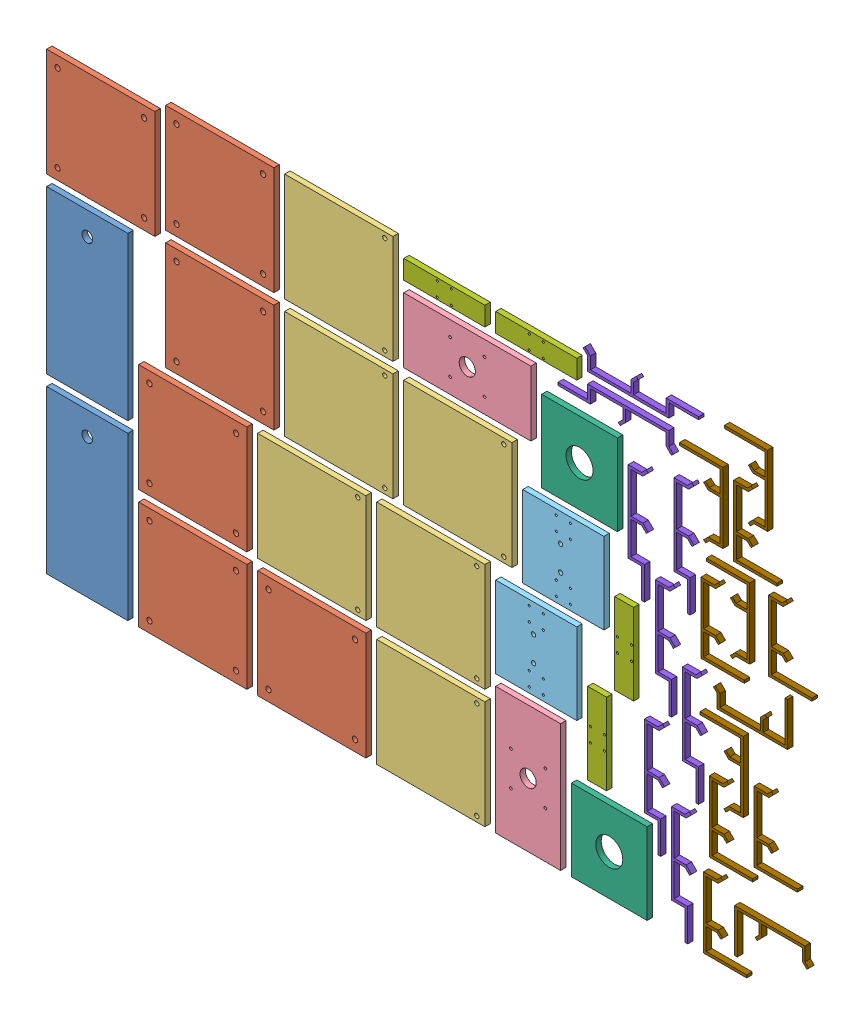
SolidWorks assembly New_Nesting(10mm), configuration Layout1[Steel_10mm_Qnty1]. Lengths in mm.
Overall size (1800 900 10).
44 component instances, 9 part files, 0 mates.
Components (placement in the parent):
- Z_Top_Plate-1: Z_Top_Plate [Default] at (85 160 0) x (1 0 0) z (0 0 -1) size (150 300 10)
- Z_Top_Plate-2: Z_Top_Plate [Default] at (85 480 0) x (1 0 0) z (0 0 -1) size (150 300 10)
- Base_Plate_X-1: Base_Plate_X [Default] at (110 750 0) x (0 -1 0) z (1 0 0) size (200 10 200)
- Base_Plate_X-2: Base_Plate_X [Default] at (280 110 0) x (0 -1 0) z (1 0 0) size (200 10 200)
- Base_Plate_X-3: Base_Plate_X [Default] at (280 330 0) x (0 -1 0) z (1 0 0) size (200 10 200)
- Base_Plate_X-4: Base_Plate_X [Default] at (330 550 0) x (0 -1 0) z (1 0 0) size (200 10 200)
- Base_Plate_X-5: Base_Plate_X [Default] at (330 770 0) x (0 -1 0) z (1 0 0) size (200 10 200)
- Base_Plate_X-6: Base_Plate_X [Default] at (500 110 0) x (0 -1 0) z (1 0 0) size (200 10 200)
- Top_Plate_X-1: Top_Plate_X [Default] at (500 330 0) x (0 -1 0) z (1 0 0) size (200 10 200)
- Top_Plate_X-2: Top_Plate_X [Default] at (550 550 0) x (0 -1 0) z (1 0 0) size (200 10 200)
- Top_Plate_X-3: Top_Plate_X [Default] at (550 770 0) x (0 -1 0) z (1 0 0) size (200 10 200)
- Top_Plate_X-4: Top_Plate_X [Default] at (720 110 0) x (0 -1 0) z (1 0 0) size (200 10 200)
- Top_Plate_X-5: Top_Plate_X [Default] at (720 330 0) x (0 -1 0) z (1 0 0) size (200 10 200)
- Top_Plate_X-6: Top_Plate_X [Default] at (770 550 0) x (0 -1 0) z (1 0 0) size (200 10 200)
- Motor Extension Plate-1: Motor Extension Plate [Default] at (787.5 730 0) x (1 0 0) z (0 0 -1) size (235 120 10)
- Motor Extension Plate-2: Motor Extension Plate [Default] at (900 127.5 0) x (0 -1 0) z (0 0 -1) size (235 120 10)
- Horizontal_Plate-1: Horizontal_Plate [Default] at (915 340 0) x (0 -1 0) z (1 0 0) size (150 10 150)
- Horizontal_Plate-2: Horizontal_Plate [Default] at (965 510 0) x (0 -1 0) z (1 0 0) size (150 10 150)
- Vertical_Plate-1: Vertical_Plate [Default] at (995 680 0) x (0 -1 0) z (0 0 -1) size (150 140 10)
- Vertical_Plate-2: Vertical_Plate [Default] at (1050 85 0) x (0 -1 0) z (0 0 -1) size (150 140 10)
- Lower_Section-1: Lower_Section [Default] at (670 810 0) x (0 0 -1) z (0 -1 0) size (10 150 35)
- Lower_Section-2: Lower_Section [Default] at (840 810 0) x (0 0 -1) z (0 -1 0) size (10 150 35)
- Lower_Section-3: Lower_Section [Default] at (1045 180 0) x (0 0 -1) z (1 0 0) size (10 150 35)
- Lower_Section-4: Lower_Section [Default] at (1095 348.6603 0) x (0 0 -1) z (1 0 0) size (10 150 35)
- Drag_Chain_Bracket_Y-1: Drag_Chain_Bracket_Y [Default] at (1117.5 797.727 -10) x (-1 0 0) z (0 0 1) size (213.49 37.02 10)
- Drag_Chain_Bracket_Y-2: Drag_Chain_Bracket_Y [Default] at (1101.3648 679.8205 -10) x (0 -1 0) z (0 0 1) size (213.49 37.02 10)
- Drag_Chain_Bracket_Y-3: Drag_Chain_Bracket_Y [Default] at (1052.5 850.4565 -10) size (213.49 37.02 10)
- Drag_Chain_Bracket_Y-4: Drag_Chain_Bracket_Y [Default] at (1131.3648 287.5 -10) x (0 -1 0) z (0 0 1) size (213.49 37.02 10)
- Drag_Chain_Bracket_Y-5: Drag_Chain_Bracket_Y [Default] at (1151.3648 520.6431 -10) x (0 -1 0) z (0 0 1) size (213.49 37.02 10)
- Drag_Chain_Bracket_Y-6: Drag_Chain_Bracket_Y [Default] at (1181.3648 172.5 -10) x (0 -1 0) z (0 0 1) size (213.49 37.02 10)
- Drag_Chain_Bracket_Y-7: Drag_Chain_Bracket_Y [Default] at (1185.8648 701.1994 -10) x (0 -1 0) z (0 0 1) size (213.49 37.02 10)
- Drag_Chain_Bracket_Y-8: Drag_Chain_Bracket_Y [Default] at (1201.3648 405.837 -10) x (0 -1 0) z (0 0 1) size (213.49 37.02 10)
- Drag_Chain_Bracket-1: Drag_Chain_Bracket [Default] at (1252.5581 548.0308 -10) x (0 -1 0) z (0 0 1) size (137.07 80 10)
- Drag_Chain_Bracket-2: Drag_Chain_Bracket [Default] at (1226.9419 736.769 -10) x (0 1 0) z (0 0 1) size (137.07 80 10)
- Drag_Chain_Bracket-3: Drag_Chain_Bracket [Default] at (1257.15 78.5359 -10) x (0 -1 0) z (0 0 1) size (137.07 80 10)
- Drag_Chain_Bracket-4: Drag_Chain_Bracket [Default] at (1268.0581 237.6785 -10) x (0 -1 0) z (0 0 1) size (137.07 80 10)
- Drag_Chain_Bracket-5: Drag_Chain_Bracket [Default] at (1264.6199 324.8011 -10) x (0 1 0) z (0 0 1) size (137.07 80 10)
- Drag_Chain_Bracket-6: Drag_Chain_Bracket [Default] at (1276.4419 576.4641 -10) x (0 1 0) z (0 0 1) size (137.07 80 10)
- Drag_Chain_Bracket-7: Drag_Chain_Bracket [Default] at (1313.0581 733.5359 -10) x (0 -1 0) z (0 0 1) size (137.07 80 10)
- Drag_Chain_Bracket-8: Drag_Chain_Bracket [Default] at (1309.6199 805.4987 -10) x (0 1 0) z (0 0 1) size (137.07 80 10)
- Drag_Chain_Bracket-9: Drag_Chain_Bracket [Default] at (1310.9608 446.3951 -10) size (137.07 80 10)
- Drag_Chain_Bracket-10: Drag_Chain_Bracket [Default] at (1350.3058 81.9419 -10) x (-1 0 0) z (0 0 1) size (137.07 80 10)
- Drag_Chain_Bracket-11: Drag_Chain_Bracket [Default] at (1350.7361 262.6785 -10) x (0 -1 0) z (0 0 1) size (137.07 80 10)
- Drag_Chain_Bracket-12: Drag_Chain_Bracket [Default] at (1377.6095 581.8729 -10) x (0 -1 0) z (0 0 1) size (137.07 80 10)
